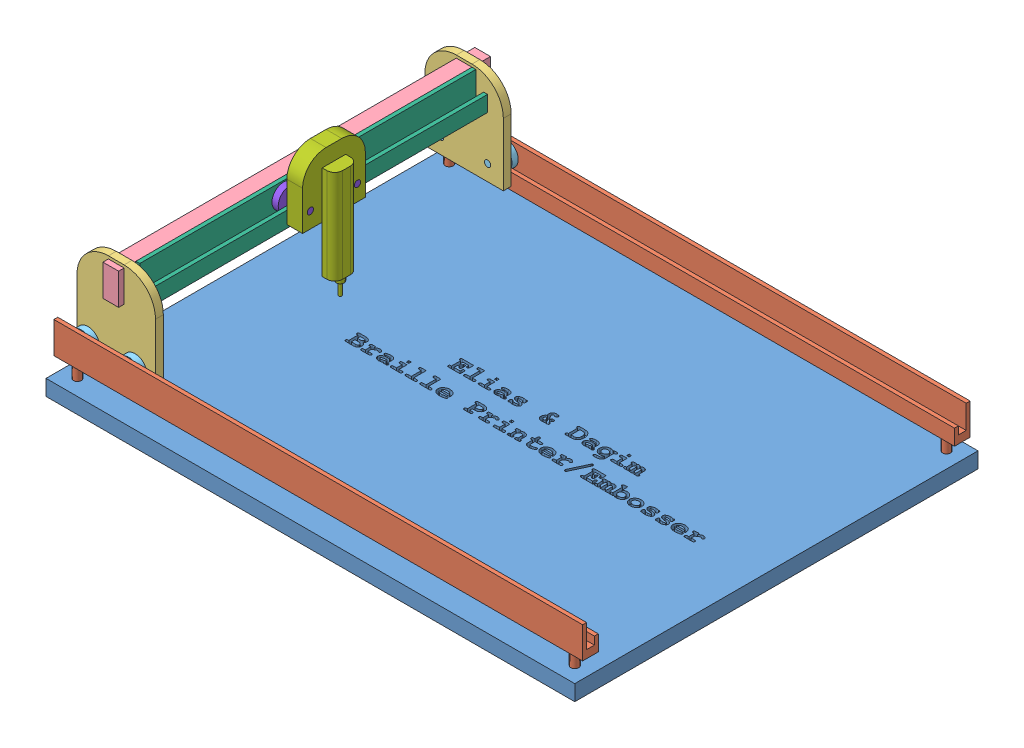
SolidWorks assembly Assem2-First_Trial, configuration Default. Lengths in mm.
Overall size (337 103.27 257).
14 component instances, 8 part files, 45 mates.
Components (placement in the parent):
- Part1-Bed-1: Part1-Bed [Default] at (91.9953 153.1249 291.9603) size (337 10 257)
- Part2-Side_Rail-1: Part2-Side_Rail [Default] at (92.2352 173.1249 410.4603) x (-1 0 0) z (0 0 -1) size (337 40 10)
- Part3-Slider-1: Part3-Slider [Default] at (-46.5074 175.6249 402.9416) size (50 60 5)
- Part4-Cross_Connecter-1: Part4-Cross_Connecter [Default] at (-46.5074 213.8963 290.4416) size (10 20 237)
- Part5-Roller_Ball-1: Part5-Roller_Ball [Default] at (-61.5074 185.6249 408.4416) x (0 0 1) z (-0.607261 -0.794502 0) size (12 15 15)
- Part2-Side_Rail-2: Part2-Side_Rail [Default] at (92.2352 173.1249 173.4603) size (337 40 10)
- Part5-Roller_Ball-2: Part5-Roller_Ball [Default] at (-31.5074 185.6249 175.7482) x (0 0 -1) z (0.607261 -0.794502 0) size (12 15 15)
- Part5-Roller_Ball-3: Part5-Roller_Ball [Default] at (-61.5074 185.6249 175.7482) x (0 0 -1) z (0.982292 0.187357 0) size (12 15 15)
- Part5-Roller_Ball-4: Part5-Roller_Ball [Default] at (-31.5074 185.6249 408.4416) x (0 0 1) z (-0.607261 -0.794502 0) size (12 15 15)
- Part3-Slider-3: Part3-Slider [Default] at (-46.5074 175.6249 181.2482) x (-1 0 0) z (0 0 -1) size (50 60 5)
- Part6-X-Side-Rail-1: Part6-X-Side-Rail [Default] at (-36.5074 213.8963 290.4416) x (0 0 1) z (-1 0 0) size (215 20 20)
- Part7-X-Slider-1: Part7-X-Slider [Default] at (-26.156 216.3963 292.0544) x (0 0 -1) z (1 0 0) size (40 82 18)
- Part5-Roller_Ball - 2-1: Part5-Roller_Ball - 2 [Default] at (-34.156 226.3963 307.0544) x (-1 0 0) z (0 0 -1) size (17 15 15)
- Part5-Roller_Ball - 2-2: Part5-Roller_Ball - 2 [Default] at (-34.156 226.3963 277.0544) x (-1 0 0) z (0 0 -1) size (17 15 15)
Mates (geometry in assembly coordinates):
- Concentric4: concentric aligned: cylinder of Part3-Slider-1 through (-31.5074 185.6249 400.4416) axis (0 0 1) radius 2; cylinder of Part5-Roller_Ball-4 through (-31.5074 185.6249 400.4416) axis (0 0 1) radius 2
- Concentric5: concentric aligned: cylinder of Part3-Slider-1 through (-61.5074 185.6249 400.4416) axis (0 0 1) radius 2; cylinder of Part5-Roller_Ball-1 through (-61.5074 185.6249 400.4416) axis (0 0 1) radius 2
- Coincident2: coincident aligned: plane of Part3-Slider-1 through (-21.5074 235.6249 400.4416) normal (0 0 -1); plane of Part5-Roller_Ball-1 through (-61.5074 185.6249 400.4416) normal (0 0 -1)
- Coincident3: coincident aligned: plane of Part3-Slider-1 through (-21.5074 235.6249 400.4416) normal (0 0 -1); plane of Part5-Roller_Ball-4 through (-31.5074 185.6249 400.4416) normal (0 0 -1)
- Concentric6: concentric aligned: cylinder of Part5-Roller_Ball-3 through (-61.5074 185.6249 183.7482) axis (0 0 -1) radius 2; cylinder of Part3-Slider-3 through (-61.5074 185.6249 183.7482) axis (0 0 -1) radius 2
- Concentric7: concentric aligned: cylinder of Part5-Roller_Ball-2 through (-31.5074 185.6249 183.7482) axis (0 0 -1) radius 2; cylinder of Part3-Slider-3 through (-31.5074 185.6249 183.7482) axis (0 0 -1) radius 2
- Coincident4: coincident aligned: plane of Part5-Roller_Ball-2 through (-31.5074 185.6249 183.7482) normal (0 0 1); plane of Part3-Slider-3 through (-71.5074 235.6249 183.7482) normal (0 0 1)
- Coincident5: coincident aligned: circle of Part5-Roller_Ball-3; plane of Part3-Slider-3 through (-71.5074 235.6249 183.7482) normal (0 0 1)
- Parallel1: parallel anti-aligned: plane of Part1-Bed-1 through (91.9953 163.1249 291.9603) normal (0 1 0); plane of Part3-Slider-3 through (-46.5074 175.6249 181.2482) normal (0 -1 0)
- Concentric8: concentric aligned: cylinder of Part1-Bed-1 through (250.7352 153.1249 173.4603) axis (0 1 0) radius 2.5; cylinder of Part2-Side_Rail-2 through (250.7352 153.1249 173.4603) axis (0 1 0) radius 2.5
- Concentric9: concentric aligned: cylinder of Part1-Bed-1 through (-66.2648 153.1249 173.4603) axis (0 1 0) radius 2.5; cylinder of Part2-Side_Rail-2 through (-66.2648 153.1249 173.4603) axis (0 1 0) radius 2.5
- Coincident10: coincident aligned: plane of Part1-Bed-1 through (91.9953 153.1249 291.9603) normal (0 -1 0); plane of Part2-Side_Rail-2 through (-66.2648 153.1249 173.4603) normal (0 -1 0)
- Parallel4: parallel aligned: plane of Part2-Side_Rail-2 through (-76.2648 178.1249 178.4603) normal (0 0 1); plane of Part3-Slider-3 through (-71.5074 235.6249 183.7482) normal (0 0 1)
- Parallel5: parallel anti-aligned: plane of Part2-Side_Rail-1 through (92.2352 173.1249 410.4603) normal (0 -1 0); plane of assembly through (0 0 0) normal (0 1 0)
- Concentric11: concentric aligned: cylinder of Part1-Bed-1 through (250.7352 153.1249 410.4603) axis (0 1 0) radius 2.5; cylinder of Part2-Side_Rail-1 through (250.7352 153.1249 410.4603) axis (0 1 0) radius 2.5
- Concentric12: concentric aligned: cylinder of Part1-Bed-1 through (-66.2648 153.1249 410.4603) axis (0 1 0) radius 2.5; cylinder of Part2-Side_Rail-1 through (-66.2648 153.1249 410.4603) axis (0 1 0) radius 2.5
- Coincident15: coincident aligned: plane of Part1-Bed-1 through (91.9953 153.1249 291.9603) normal (0 -1 0); plane of Part2-Side_Rail-1 through (-66.2648 153.1249 410.4603) normal (0 -1 0)
- Parallel6: parallel anti-aligned: plane of Part2-Side_Rail-1 through (260.7352 193.1249 412.9603) normal (0 0 -1); plane of Part3-Slider-1 through (-21.5074 235.6249 405.4416) normal (0 0 1)
- Parallel7: parallel anti-aligned: plane of Part3-Slider-1 through (-21.5074 235.6249 400.4416) normal (0 0 -1); plane of Part3-Slider-3 through (-71.5074 235.6249 183.7482) normal (0 0 1)
- Tangent2: tangent anti-aligned: plane of Part2-Side_Rail-1 through (92.2352 178.1249 410.4603) normal (0 1 0); cylinder of Part5-Roller_Ball-4 through (-31.5074 185.6249 412.4416) axis (0 0 -1) radius 7.5
- Tangent3: tangent anti-aligned: plane of Part2-Side_Rail-1 through (92.2352 178.1249 410.4603) normal (0 1 0); cylinder of Part5-Roller_Ball-1 through (-61.5074 185.6249 412.4416) axis (0 0 -1) radius 7.5
- Tangent4: tangent anti-aligned: plane of Part2-Side_Rail-2 through (92.2352 178.1249 173.4603) normal (0 1 0); cylinder of Part5-Roller_Ball-3 through (-61.5074 185.6249 171.7482) axis (0 0 1) radius 7.5
- Tangent5: tangent anti-aligned: plane of Part2-Side_Rail-2 through (92.2352 178.1249 173.4603) normal (0 1 0); cylinder of Part5-Roller_Ball-2 through (-31.5074 185.6249 171.7482) axis (0 0 1) radius 7.5
- Coincident18: coincident anti-aligned: plane of Part4-Cross_Connecter-1 through (-51.5074 233.8963 171.9416) normal (-1 0 0); plane of Part3-Slider-3 through (-51.5074 233.8963 183.7482) normal (1 0 0)
- Coincident19: coincident anti-aligned: plane of Part3-Slider-1 through (-51.5074 233.8963 400.4416) normal (1 0 0); plane of Part4-Cross_Connecter-1 through (-51.5074 233.8963 171.9416) normal (-1 0 0)
- Coincident21: coincident anti-aligned: plane of Part4-Cross_Connecter-1 through (-46.5074 213.8963 290.4416) normal (0 -1 0); plane of Part3-Slider-3 through (-41.5074 213.8963 183.7482) normal (0 1 0)
- Coincident22: coincident anti-aligned: plane of Part3-Slider-1 through (-51.5074 213.8963 400.4416) normal (0 1 0); plane of Part4-Cross_Connecter-1 through (-46.5074 213.8963 290.4416) normal (0 -1 0)
- Distance1: distance = 3.5 mm aligned: plane of Part3-Slider-1 through (-21.5074 235.6249 405.4416) normal (0 0 1); plane of Part4-Cross_Connecter-1 through (-51.5074 233.8963 408.9416) normal (0 0 1)
- Parallel8: parallel anti-aligned: plane of Part1-Bed-1 through (91.9953 153.1249 291.9603) normal (0 -1 0); plane of Part6-X-Side-Rail-1 through (-36.5074 218.8963 290.4416) normal (0 1 0)
- Parallel9: parallel anti-aligned: plane of Part1-Bed-1 through (91.9953 163.1249 291.9603) normal (0 1 0); plane of Part6-X-Side-Rail-1 through (-36.5074 213.8963 290.4416) normal (0 -1 0)
- Concentric14: concentric aligned: cylinder of Part4-Cross_Connecter-1 through (-51.5074 223.8963 387.9416) axis (1 0 0) radius 2.5; cylinder of Part6-X-Side-Rail-1 through (-51.5074 223.8963 387.9416) axis (1 0 0) radius 2.5
- Coincident25: coincident aligned: plane of Part4-Cross_Connecter-1 through (-51.5074 233.8963 171.9416) normal (-1 0 0); plane of Part6-X-Side-Rail-1 through (-51.5074 223.8963 192.9416) normal (-1 0 0)
- Concentric19: concentric anti-aligned: cylinder of Part7-X-Slider-1 through (-31.156 226.3963 277.0544) axis (1 0 0) radius 2; cylinder of Part5-Roller_Ball - 2-2 through (-21.156 226.3963 277.0544) axis (-1 0 0) radius 2
- Concentric20: concentric anti-aligned: cylinder of Part7-X-Slider-1 through (-31.156 226.3963 307.0544) axis (1 0 0) radius 2; cylinder of Part5-Roller_Ball - 2-1 through (-21.156 226.3963 307.0544) axis (-1 0 0) radius 2
- Coincident28: coincident aligned: plane of Part7-X-Slider-1 through (-21.156 256.3963 312.0544) normal (1 0 0); plane of Part5-Roller_Ball - 2-2 through (-21.156 226.3963 277.0544) normal (1 0 0)
- Coincident30: coincident aligned: plane of Part7-X-Slider-1 through (-21.156 256.3963 312.0544) normal (1 0 0); plane of Part5-Roller_Ball - 2-1 through (-21.156 226.3963 307.0544) normal (1 0 0)
- Parallel10: parallel anti-aligned: plane of Part1-Bed-1 through (91.9953 163.1249 291.9603) normal (0 1 0); plane of Part7-X-Slider-1 through (-26.156 216.3963 292.0544) normal (0 -1 0)
- Parallel11: parallel anti-aligned: plane of Part6-X-Side-Rail-1 through (-31.5074 218.8963 182.9416) normal (1 0 0); plane of Part7-X-Slider-1 through (-31.156 256.3963 312.0544) normal (-1 0 0)
- Coincident32: coincident: plane of Part2-Side_Rail-2 through (-76.2648 178.1249 178.4603) normal (0 0 1); plane of Part3-Slider-3 through (-71.5074 235.6249 178.4603) normal (0 0 -1)
- Coincident33: coincident anti-aligned: plane of Part2-Side_Rail-2 through (-76.2648 178.1249 178.4603) normal (0 0 1); plane of Part3-Slider-3 through (-71.4669 235.6249 178.4603) normal (0 0 -1)
- Coincident34: coincident: plane of Part2-Side_Rail-2 through (-76.2648 178.1249 178.4603) normal (0 0 1); plane of Part3-Slider-3 through (-71.5074 235.6249 178.4603) normal (0 0 -1)
- Coincident35: coincident anti-aligned: plane of Part2-Side_Rail-2 through (-76.2648 178.1249 178.4603) normal (0 0 1); plane of Part3-Slider-3 through (66.9844 235.6372 178.4715) normal (0.000009 0.000195 -1)
- Coincident37: coincident: plane of Part2-Side_Rail-1 through (260.7352 178.1249 405.4603) normal (0 0 -1); plane of Part3-Slider-1 through (-21.5074 235.6249 405.4603) normal (0 0 1)
- Coincident38: coincident: plane of Part6-X-Side-Rail-1 through (-31.5074 218.8963 182.9416) normal (1 0 0); plane of Part7-X-Slider-1 through (-31.5074 256.3963 312.0544) normal (-1 0 0)
- Coincident39: coincident: plane of Part6-X-Side-Rail-1 through (-31.5074 218.8963 182.9603) normal (1 0 0); plane of Part7-X-Slider-1 through (-31.5074 256.3963 395.4529) normal (-1 0 0)
